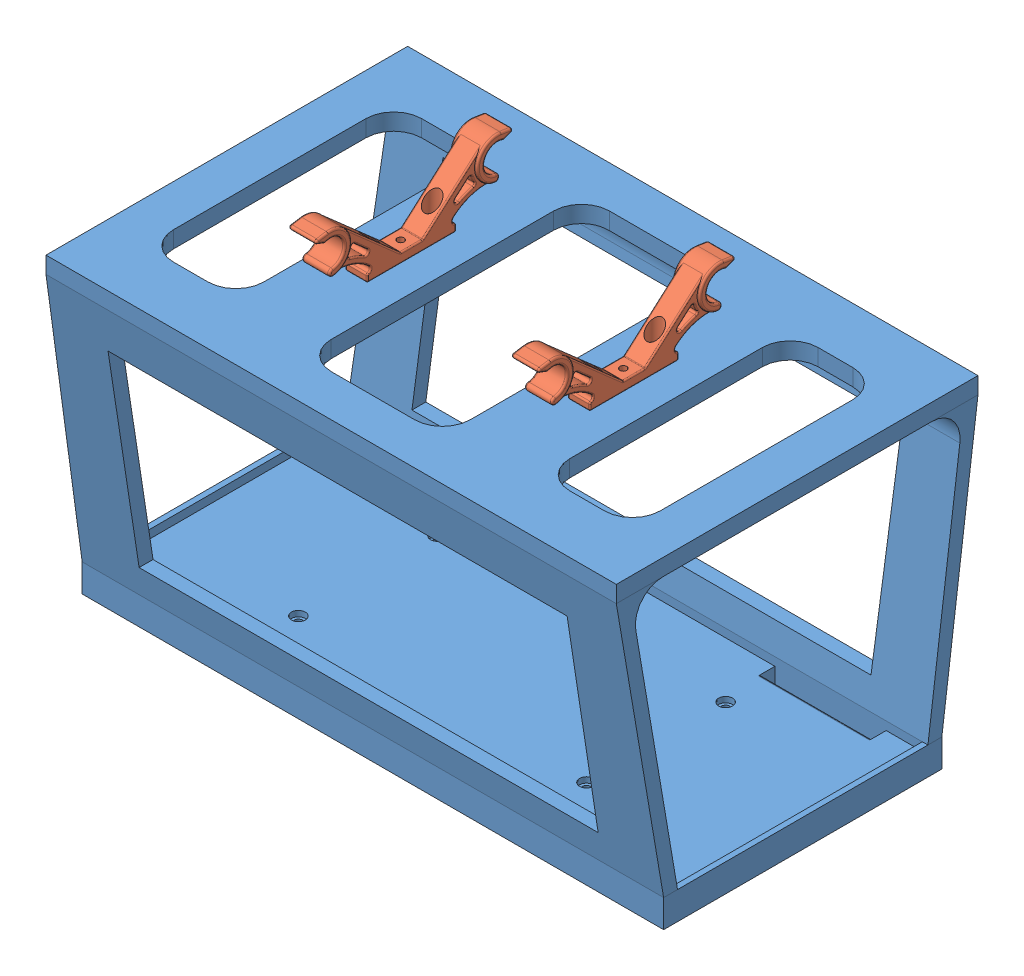
SolidWorks assembly Battery_Box_ASSEMBLED, configuration Default. Lengths in mm.
Overall size (209.01 137.94 130).
3 component instances, 2 part files, 7 mates.
Components (placement in the parent):
- BatteryMount-1: BatteryMount [Default] at origin size (209.01 114 130)
- BatteryMountClip-3: BatteryMountClip [Default] at (-40 104 0) x (0 0 -1) z (0 1 0) size (70.63 10.03 23.94)
- BatteryMountClip-4: BatteryMountClip [Default] at (40 104 0) x (0 0 -1) z (0 1 0) size (70.63 10.03 23.94)
Mates (geometry in assembly coordinates):
- Coincident1: coordinate: point of BatteryMount-1
- Concentric2: concentric anti-aligned: circle of BatteryMount-1; circle of BatteryMountClip-3
- Concentric3: concentric anti-aligned: circle of BatteryMount-1; circle of BatteryMountClip-3
- Coincident3: coincident anti-aligned: plane of BatteryMount-1 through (0 104 0) normal (0 1 0); plane of BatteryMountClip-3 through (-40 104 0) normal (0 -1 0)
- Concentric4: concentric anti-aligned: circle of BatteryMount-1; circle of BatteryMountClip-4
- Concentric5: concentric anti-aligned: circle of BatteryMount-1; circle of BatteryMountClip-4
- Coincident4: coincident anti-aligned: plane of BatteryMount-1 through (0 104 0) normal (0 1 0); plane of BatteryMountClip-4 through (40 104 0) normal (0 -1 0)
